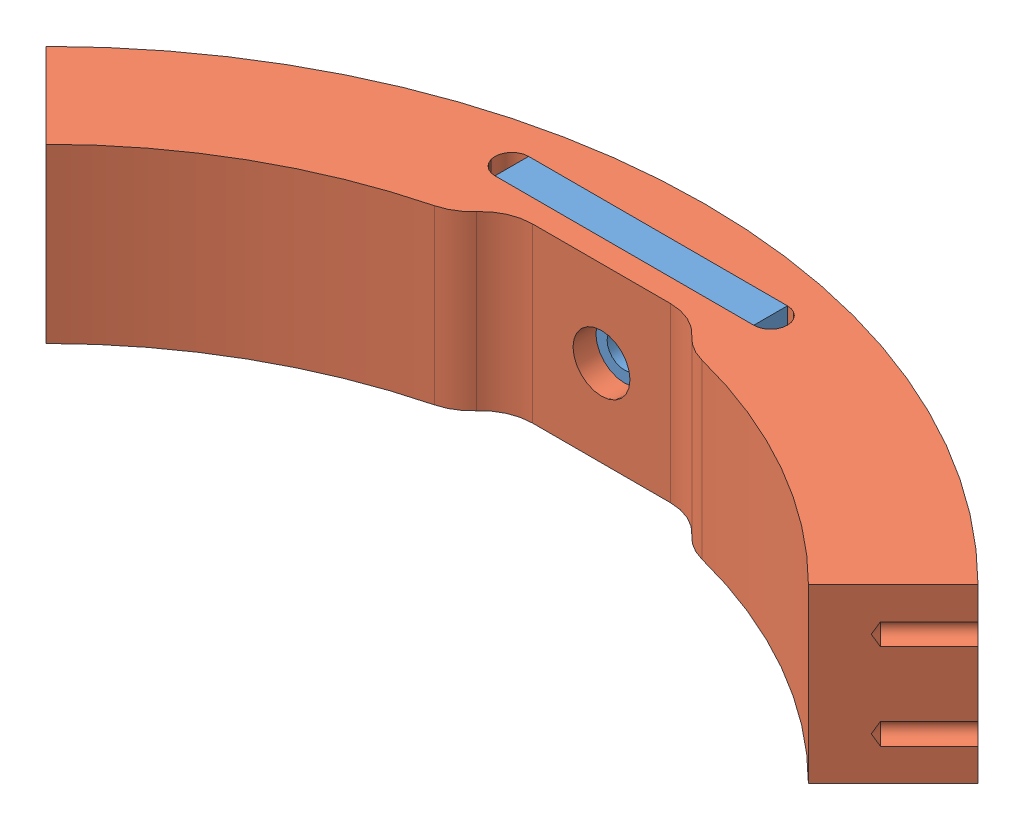
SolidWorks assembly TEST Brute, configuration Default. Lengths in mm.
Overall size (108.12 20 32.21).
2 component instances, 2 part files, 2 mates.
Components (placement in the parent):
- 113201_Mini_Rod-1: 113201_Mini_Rod [Valve_Bay] at (3.4529 7.3427 24.0185) size (30 20 3.9)
- xcadmodel-R1132100926410-00001120-1: xcadmodel-R1132100926410-00001120 [TEST Topo] at (3.4529 7.3427 94.9685) x (1 0 0) z (0 1 0) size (108.12 32.21 20)
Mates (geometry in assembly coordinates):
- Coincident1: coincident: plane of 113201_Mini_Rod-1 through (3.4529 7.3427 27.9185) normal (0 0 1); plane of xcadmodel-R1132100926410-00001120-1 through (3.4529 27.3427 27.9185) normal (0 0 -1)
- Coincident2: coincident: point of 113201_Mini_Rod-1; point of xcadmodel-R1132100926410-00001120-1
